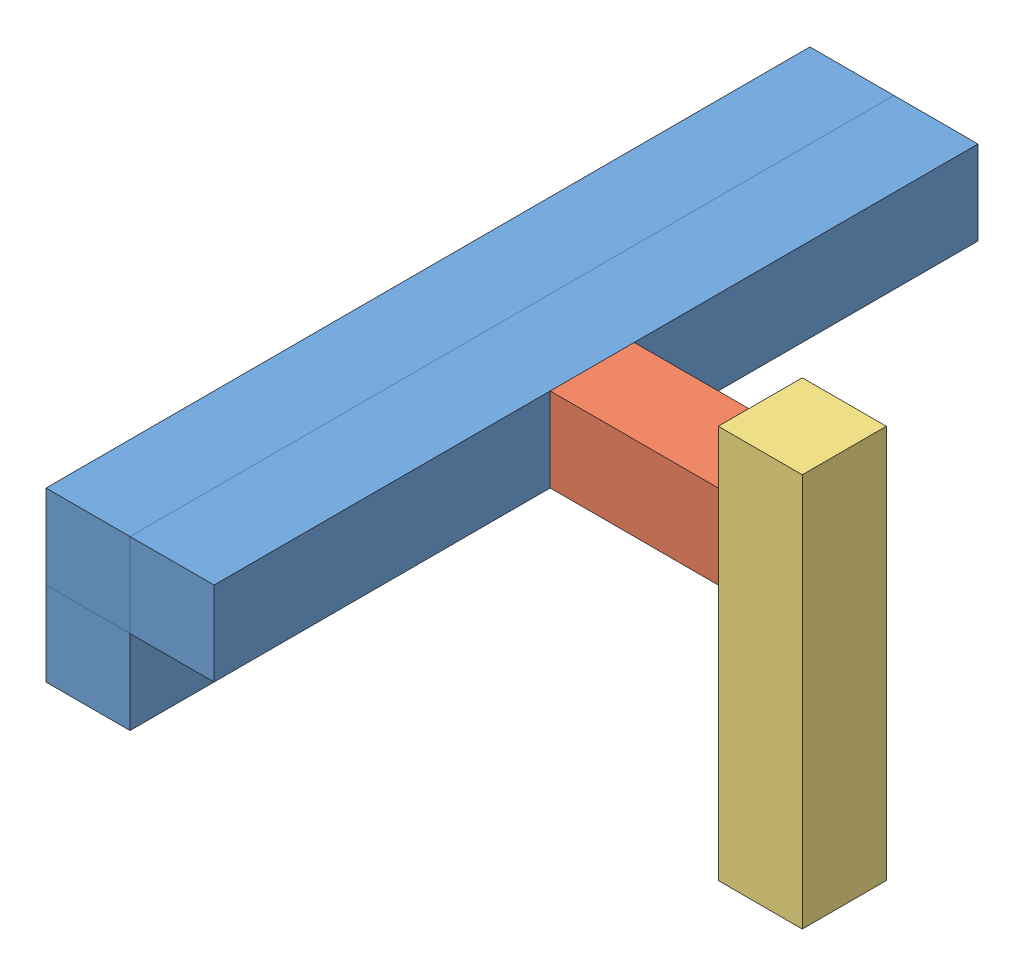
SolidWorks assembly porte_message_rouge, configuration Default. Lengths in mm.
Overall size (110 103 200).
5 component instances, 3 part files, 12 mates.
Components (placement in the parent):
- linteau_22x22_L200_rouge-1: linteau_22x22_L200_rouge [Default] at (-44.0703 -4.4681 113.0131) size (22 22 200)
- linteau_22x22_L200_rouge-2: linteau_22x22_L200_rouge [Default] at (-22.0703 -4.4681 113.0131) size (22 22 200)
- linteau_22x22_L44_rouge-1: linteau_22x22_L44_rouge [Default] at (-0.0703 -4.4681 3.0131) x (0 0 1) z (-1 0 0) size (22 22 44)
- linteau_22x22_L103_rouge-1: linteau_22x22_L103_rouge [Default] at (43.9297 -71.4681 3.0131) x (1 0 0) z (0 -1 0) size (22 22 103)
- linteau_22x22_L200_rouge-3: linteau_22x22_L200_rouge [Default] at (-44.0703 -26.4681 113.0131) size (22 22 200)
Mates (geometry in assembly coordinates):
- Coïncidente1: coincident aligned: plane of linteau_22x22_L200_rouge-2 through (-22.0703 17.5319 -86.9869) normal (0 1 0); plane of linteau_22x22_L200_rouge-1 through (-44.0703 17.5319 -86.9869) normal (0 1 0)
- Coïncidente2: coincident aligned: plane of linteau_22x22_L200_rouge-1 through (-44.0703 17.5319 113.0131) normal (0 0 1); plane of linteau_22x22_L200_rouge-2 through (-22.0703 17.5319 113.0131) normal (0 0 1)
- Coïncidente3: coincident anti-aligned: plane of linteau_22x22_L200_rouge-1 through (-22.0703 -4.4681 -86.9869) normal (1 0 0); plane of linteau_22x22_L200_rouge-2 through (-22.0703 -4.4681 -86.9869) normal (-1 0 0)
- Coïncidente4: coincident anti-aligned: plane of linteau_22x22_L200_rouge-2 through (-0.0703 -4.4681 -86.9869) normal (1 0 0); plane of linteau_22x22_L44_rouge-1 through (-0.0703 17.5319 3.0131) normal (-1 0 0)
- Coïncidente5: coincident aligned: plane of linteau_22x22_L200_rouge-2 through (-22.0703 17.5319 -86.9869) normal (0 1 0); plane of linteau_22x22_L44_rouge-1 through (43.9297 17.5319 3.0131) normal (0 1 0)
- Distance1: distance = 88 mm aligned: plane of linteau_22x22_L44_rouge-1 through (43.9297 -4.4681 25.0131) normal (0 0 1); plane of linteau_22x22_L200_rouge-2 through (-22.0703 17.5319 113.0131) normal (0 0 1)
- Coïncidente7: coincident anti-aligned: plane of linteau_22x22_L44_rouge-1 through (43.9297 17.5319 3.0131) normal (1 0 0); plane of linteau_22x22_L103_rouge-1 through (43.9297 31.5319 3.0131) normal (-1 0 0)
- Coïncidente8: coincident aligned: plane of linteau_22x22_L103_rouge-1 through (43.9297 31.5319 25.0131) normal (0 0 1); plane of linteau_22x22_L44_rouge-1 through (43.9297 -4.4681 25.0131) normal (0 0 1)
- Distance2: distance = 67 mm aligned: plane of linteau_22x22_L103_rouge-1 through (43.9297 -71.4681 25.0131) normal (0 -1 0); plane of linteau_22x22_L200_rouge-2 through (-22.0703 -4.4681 -86.9869) normal (0 -1 0)
- Coïncidente9: coincident: plane of linteau_22x22_L200_rouge-1 through (-44.0703 17.5319 113.0131) normal (0 0 1); plane of ? through (-72.1716 -4.4681 113.0131) normal (0 0 1)
- Coïncidente10: coincident: plane of linteau_22x22_L200_rouge-1 through (-44.0703 -4.4681 -86.9869) normal (0 -1 0); plane of ? through (-72.1716 -4.4681 -86.9869) normal (0 1 0)
- Coïncidente11: coincident aligned: plane of linteau_22x22_L200_rouge-1 through (-44.0703 -4.4681 -86.9869) normal (-1 0 0); plane of ? through (-72.1716 -26.4681 -86.9869) normal (-1 0 0)
